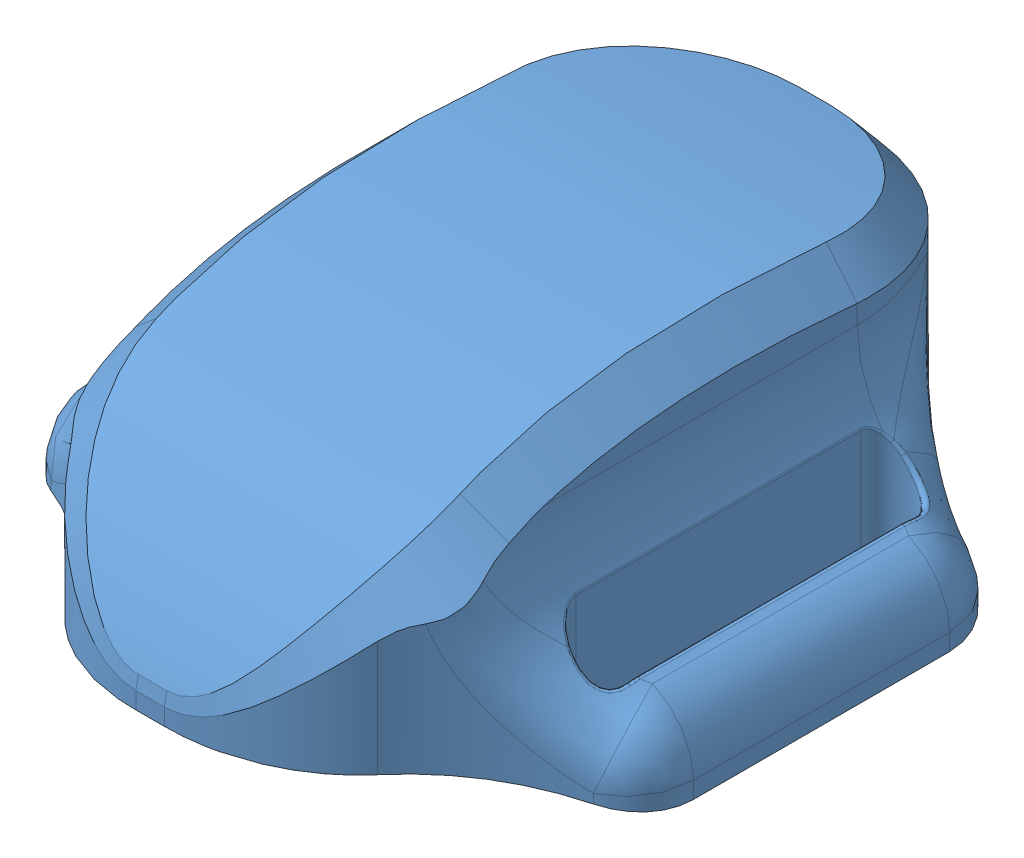
SolidWorks assembly Assem1, configuration Default. Lengths in mm.
Overall size (89.98 40.26 100.71).
2 component instances, 2 part files, 0 mates.
Components (placement in the parent):
- Case Proto - 1-1: Case Proto - 1 [Default] at (-40.2524 -11.8349 0.8069) size (89.98 40.26 100.71)
- Circuit Board-1: Circuit Board [Default] at (-40.6886 -5.9027 11.4812) size (32 21 55)
